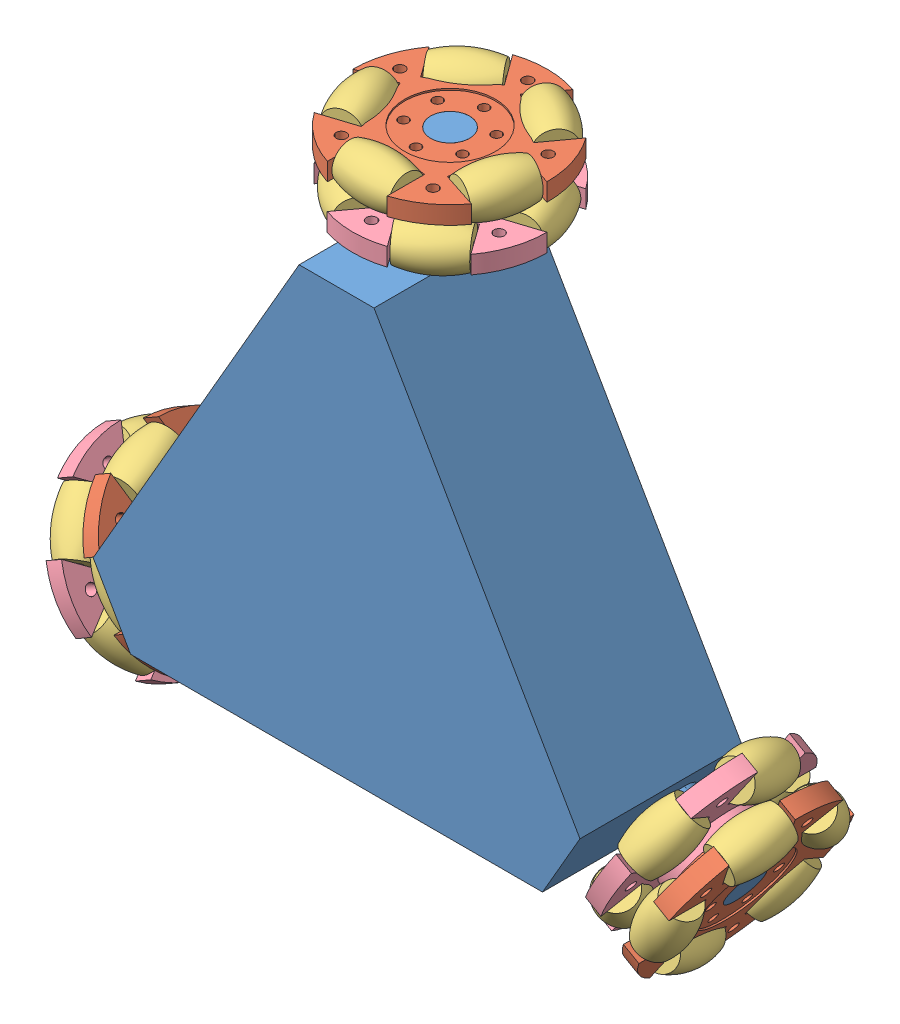
SolidWorks assembly Assem1, configuration Default. Lengths in mm.
Overall size (230.32 199.46 75.74).
40 component instances, 4 part files, 6 mates.
Components (placement in the parent):
- base.step-1: base.step [Default] at origin size (187.87 162.7 50)
- RodaOmni 60 mm.stp-1: RodaOmni 60 mm.stp [Default] at (-76.0608 -47.2632 16.8302) x (0.866025 0.5 0) z (0 0 1) size (30.22 75.74 75.74)
  - Dasar.stp-1: Dasar.stp [Default] at (-2.4978 2.9007 -1.8302) x (1 0 0) z (0 -0.312449 -0.949935) size (9.5 58.55 60)
  - Roller.stp-1: Roller.stp [Default] at (-21.4546 23.8825 4.9122) x (0 -0.95216 -0.305599) z (0 -0.305599 0.95216) size (16.72 16.72 17.64)
  - Roller.stp-2: Roller.stp [Default] at (-21.4546 15.7983 -19.7005) x (0 -0.584876 0.811123) z (0 0.811123 0.584876) size (16.72 16.72 17.64)
  - Roller.stp-3: Roller.stp [Default] at (21.959 -18.0364 5.0495) x (0 0.949941 -0.312431) z (0 0.312431 0.949941) size (16.72 16.72 17.64)
  - Roller.stp-4: Roller.stp [Default] at (21.959 -10.1083 -19.6195) x (0 0.590687 0.806901) z (0 -0.806901 0.590687) size (16.72 16.72 17.64)
  - Roller.stp-5: Roller.stp [Default] at (-21.4546 2.9733 20.2081) x (0 -0.003591 -0.999994) z (0 -0.999994 0.003591) size (16.72 16.72 17.64)
  - Dasar_1.stp-1: Dasar_1.stp [Default] at (-10.4978 2.9007 -1.8302) x (-1 0 0) z (0 -0.312412 -0.949947) size (9.5 58.55 60)
  - Roller.stp-6: Roller.stp [Default] at (8.459 -18.0863 -8.5561) x (0 0.95216 0.305599) z (0 -0.305599 0.95216) size (16.72 16.72 17.64)
  - Roller.stp-7: Roller.stp [Default] at (8.459 -9.9826 16.0503) x (0 0.584876 -0.811123) z (0 0.811123 0.584876) size (16.72 16.72 17.64)
  - Roller.stp-8: Roller.stp [Default] at (-34.9546 23.8341 -8.7214) x (0 -0.949941 0.312431) z (0 0.312431 0.949941) size (16.72 16.72 17.64)
  - Roller.stp-9: Roller.stp [Default] at (-34.9546 15.9238 15.9488) x (0 -0.590687 -0.806901) z (0 -0.806901 0.590687) size (16.72 16.72 17.64)
  - Roller.stp-10: Roller.stp [Default] at (8.459 2.8107 -23.8685) x (0 0.003591 0.999994) z (0 -0.999994 0.003591) size (16.72 16.72 17.64)
- RodaOmni 60 mm.stp-2: RodaOmni 60 mm.stp [Default] at (87.3153 -53.761 16.8302) x (0.866025 -0.5 0) z (0 0 1) size (30.22 75.74 75.74)
  - Dasar.stp-1: Dasar.stp [Default] at (-2.4978 2.9007 -1.8302) x (1 0 0) z (0 -0.312449 -0.949935) size (9.5 58.55 60)
  - Roller.stp-1: Roller.stp [Default] at (-21.4546 23.8825 4.9122) x (0 -0.95216 -0.305599) z (0 -0.305599 0.95216) size (16.72 16.72 17.64)
  - Roller.stp-2: Roller.stp [Default] at (-21.4546 15.7983 -19.7005) x (0 -0.584876 0.811123) z (0 0.811123 0.584876) size (16.72 16.72 17.64)
  - Roller.stp-3: Roller.stp [Default] at (21.959 -18.0364 5.0495) x (0 0.949941 -0.312431) z (0 0.312431 0.949941) size (16.72 16.72 17.64)
  - Roller.stp-4: Roller.stp [Default] at (21.959 -10.1083 -19.6195) x (0 0.590687 0.806901) z (0 -0.806901 0.590687) size (16.72 16.72 17.64)
  - Roller.stp-5: Roller.stp [Default] at (-21.4546 2.9733 20.2081) x (0 -0.003591 -0.999994) z (0 -0.999994 0.003591) size (16.72 16.72 17.64)
  - Dasar_1.stp-1: Dasar_1.stp [Default] at (-10.4978 2.9007 -1.8302) x (-1 0 0) z (0 -0.312412 -0.949947) size (9.5 58.55 60)
  - Roller.stp-6: Roller.stp [Default] at (8.459 -18.0863 -8.5561) x (0 0.95216 0.305599) z (0 -0.305599 0.95216) size (16.72 16.72 17.64)
  - Roller.stp-7: Roller.stp [Default] at (8.459 -9.9826 16.0503) x (0 0.584876 -0.811123) z (0 0.811123 0.584876) size (16.72 16.72 17.64)
  - Roller.stp-8: Roller.stp [Default] at (-34.9546 23.8341 -8.7214) x (0 -0.949941 0.312431) z (0 0.312431 0.949941) size (16.72 16.72 17.64)
  - Roller.stp-9: Roller.stp [Default] at (-34.9546 15.9238 15.9488) x (0 -0.590687 -0.806901) z (0 -0.806901 0.590687) size (16.72 16.72 17.64)
  - Roller.stp-10: Roller.stp [Default] at (8.459 2.8107 -23.8685) x (0 0.003591 0.999994) z (0 -0.999994 0.003591) size (16.72 16.72 17.64)
- RodaOmni 60 mm.stp-3: RodaOmni 60 mm.stp [Default] at (2.9007 102.4978 16.8302) x (0 1 0) z (0 0 1) size (30.22 75.74 75.74)
  - Dasar.stp-1: Dasar.stp [Default] at (-2.4978 2.9007 -1.8302) x (1 0 0) z (0 -0.312449 -0.949935) size (9.5 58.55 60)
  - Roller.stp-1: Roller.stp [Default] at (-21.4546 23.8825 4.9122) x (0 -0.95216 -0.305599) z (0 -0.305599 0.95216) size (16.72 16.72 17.64)
  - Roller.stp-2: Roller.stp [Default] at (-21.4546 15.7983 -19.7005) x (0 -0.584876 0.811123) z (0 0.811123 0.584876) size (16.72 16.72 17.64)
  - Roller.stp-3: Roller.stp [Default] at (21.959 -18.0364 5.0495) x (0 0.949941 -0.312431) z (0 0.312431 0.949941) size (16.72 16.72 17.64)
  - Roller.stp-4: Roller.stp [Default] at (21.959 -10.1083 -19.6195) x (0 0.590687 0.806901) z (0 -0.806901 0.590687) size (16.72 16.72 17.64)
  - Roller.stp-5: Roller.stp [Default] at (-21.4546 2.9733 20.2081) x (0 -0.003591 -0.999994) z (0 -0.999994 0.003591) size (16.72 16.72 17.64)
  - Dasar_1.stp-1: Dasar_1.stp [Default] at (-10.4978 2.9007 -1.8302) x (-1 0 0) z (0 -0.312412 -0.949947) size (9.5 58.55 60)
  - Roller.stp-6: Roller.stp [Default] at (8.459 -18.0863 -8.5561) x (0 0.95216 0.305599) z (0 -0.305599 0.95216) size (16.72 16.72 17.64)
  - Roller.stp-7: Roller.stp [Default] at (8.459 -9.9826 16.0503) x (0 0.584876 -0.811123) z (0 0.811123 0.584876) size (16.72 16.72 17.64)
  - Roller.stp-8: Roller.stp [Default] at (-34.9546 23.8341 -8.7214) x (0 -0.949941 0.312431) z (0 0.312431 0.949941) size (16.72 16.72 17.64)
  - Roller.stp-9: Roller.stp [Default] at (-34.9546 15.9238 15.9488) x (0 -0.590687 -0.806901) z (0 -0.806901 0.590687) size (16.72 16.72 17.64)
  - Roller.stp-10: Roller.stp [Default] at (8.459 2.8107 -23.8685) x (0 0.003591 0.999994) z (0 -0.999994 0.003591) size (16.72 16.72 17.64)
Mates (geometry in assembly coordinates):
- Concentric1: concentric: cylinder of base.step-1 through (0 105 15) axis (0 -1 0) radius 6; cylinder of RodaOmni 60 mm.stp-3/Dasar_1.stp-1 through (0 87 15) axis (0 1 0) radius 6
- Coincident2: coincident aligned: plane of base.step-1 through (0 105 15) normal (0 1 0); plane of RodaOmni 60 mm.stp-3/Dasar.stp-1 through (0 105 15) normal (0 1 0)
- Concentric2: concentric: cylinder of base.step-1 through (-90.9327 -52.5 15) axis (0.866025 0.5 0) radius 6; cylinder of RodaOmni 60 mm.stp-1/Dasar.stp-1 through (-75.3442 -43.5 15) axis (-0.866025 -0.5 0) radius 6
- Coincident3: coincident aligned: plane of base.step-1 through (-90.9327 -52.5 15) normal (-0.866025 -0.5 0); plane of RodaOmni 60 mm.stp-1/Dasar_1.stp-1 through (-90.9327 -52.5 15) normal (-0.866025 -0.5 0)
- Concentric3: concentric: cylinder of base.step-1 through (90.9327 -52.5 15) axis (-0.866025 0.5 0) radius 6; cylinder of RodaOmni 60 mm.stp-2/Dasar_1.stp-1 through (75.3442 -43.5 15) axis (0.866025 -0.5 0) radius 6
- Coincident4: coincident aligned: plane of base.step-1 through (90.9327 -52.5 15) normal (0.866025 -0.5 0); plane of RodaOmni 60 mm.stp-2/Dasar.stp-1 through (90.9327 -52.5 15) normal (0.866025 -0.5 0)
